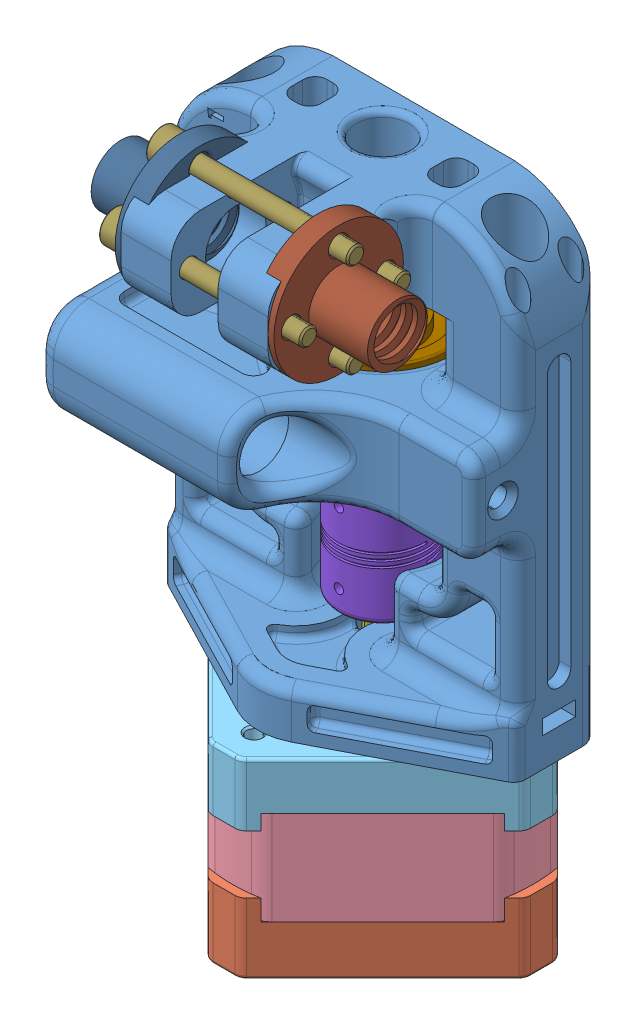
SolidWorks assembly x lead motor block, configuration Default. Lengths in mm.
Overall size (60.87 113.5 61.7).
20 component instances, 12 part files, 15 mates.
Components (placement in the parent):
- x motor lead-1: x motor lead [Default] at (-4.722 9.0941 85.25) size (60.87 77.79 39.41)
- 17HS13-0404S-1: 17HS13-0404S [По умолчанию] at (-4.722 -73.4059 92.25) x (0.707107 0 0.707107) z (-0.707107 0 0.707107) size (42 52.5 42)
  - nema17_bottom_33mm-1: nema17_bottom_33mm [По умолчанию] at origin size (42 12 42)
  - radial ball bearing_68_din-1: radial ball bearing_68_din [DIN 625 - 625 - 8,SI,NC,8_68] at (0 5 0) x (0 -1 0) z (0 0 1) size (5 16 16)
  - nema17_middle_33mm-1: nema17_middle_33mm [По умолчанию] at (0 8.5 0) size (42 16 42)
  - nema17_top_33mm-1: nema17_top_33mm [По умолчанию] at (0 24.5 0) size (42 12.6 42)
  - radial ball bearing_68_din-3: radial ball bearing_68_din [DIN 625 - 625 - 8,SI,NC,8_68] at (0 30.6 0) x (0 1 0) z (0 0 1) size (5 16 16)
  - countersunk flat head cross recess screw_din-1: countersunk flat head cross recess screw_din [ISO 7046-1 - M3 x 25 - Z --- 25N] at (15.5 0.6 15.5) x (0 1 0) z (0.546944 0 -0.837169) size (25 5.5 5.5)
  - countersunk flat head cross recess screw_din-2: countersunk flat head cross recess screw_din [ISO 7046-1 - M3 x 25 - Z --- 25N] at (15.5 0.6 -15.5) x (0 1 0) z (0.546944 0 -0.837169) size (25 5.5 5.5)
  - countersunk flat head cross recess screw_din-3: countersunk flat head cross recess screw_din [ISO 7046-1 - M3 x 25 - Z --- 25N] at (-15.5 0.6 15.5) x (0 1 0) z (0.546944 0 -0.837169) size (25 5.5 5.5)
  - countersunk flat head cross recess screw_din-4: countersunk flat head cross recess screw_din [ISO 7046-1 - M3 x 25 - Z --- 25N] at (-15.5 0.6 -15.5) x (0 1 0) z (0.546944 0 -0.837169) size (25 5.5 5.5)
  - nema17_shaft_33mm-1: nema17_shaft_33mm [По умолчанию] at (0 1.5 0) x (-0.412738 0 0.91085) z (-0.91085 0 -0.412738) size (5 51 5)
- 5-8 small-1: 5-8 small [Default] at (-4.722 -30.9059 92.25) x (1 0 0) z (0 1 0) size (15.39 15.39 20)
- instrument ball bearing_68_iso-1: instrument ball bearing_68_iso [ISO 1224 - 100822 - R,8,SI,NC,8_68] at (-4.722 6.5941 92.25) x (0 1 0) z (0 0 1) size (7 22 22)
- LeadScrew Nut 8mm x 2mmPitch (1)-2: LeadScrew Nut 8mm x 2mmPitch (1) [Default] at (-14.722 29.0941 113.25) x (0 0 -1) z (1 0 0) size (22 22 16.05)
- LeadScrew Nut 8mm x 2mmPitch (2)-2: LeadScrew Nut 8mm x 2mmPitch (2) [Default] at (5.278 29.0941 113.25) x (0 0 1) z (-1 0 0) size (22 22 16.05)
- socket head cap screw_iso-7: socket head cap screw_iso [ISO 4762 M3 x 30 - 18N] at (-21.222 37.0941 113.25) size (33 5.5 5.5)
- socket head cap screw_iso-8: socket head cap screw_iso [ISO 4762 M3 x 30 - 18N] at (-21.222 21.0941 113.25) size (33 5.5 5.5)
- socket head cap screw_iso-9: socket head cap screw_iso [ISO 4762 M3 x 30 - 18N] at (-21.222 29.0941 105.25) size (33 5.5 5.5)
- socket head cap screw_iso-10: socket head cap screw_iso [ISO 4762 M3 x 30 - 18N] at (-21.222 29.0941 121.25) size (33 5.5 5.5)
Mates (geometry in assembly coordinates):
- Coincidente2: coincident aligned: plane of 17HS13-0404S-1/nema17_shaft_33mm-1 through (-4.722 -20.9059 92.25) normal (0 1 0); plane of 5-8 small-1 through (-4.722 -20.9059 92.25) normal (0 1 0)
- Concentrico2: concentric anti-aligned: cylinder of 17HS13-0404S-1/nema17_shaft_33mm-1 through (-4.722 -20.9059 92.25) axis (0 -1 0) radius 2.5; cylinder of 5-8 small-1 through (-4.722 -20.9059 92.25) axis (0 1 0) radius 4
- Concentrico3: concentric aligned: cylinder of x motor lead-1 through (-4.722 49.0941 92.25) axis (0 1 0) radius 4.5; cylinder of instrument ball bearing_68_iso-1 through (-4.722 -14.0434 92.25) axis (0 1 0) radius 4
- Coincidente3: coincident anti-aligned: plane of x motor lead-1 through (-4.722 3.0941 92.25) normal (0 1 0); plane of instrument ball bearing_68_iso-1 through (-13.622 3.0941 92.25) normal (0 -1 0)
- Concentrico4: concentric aligned: cylinder of 5-8 small-1 through (-4.722 -20.9059 92.25) axis (0 1 0) radius 4; cylinder of instrument ball bearing_68_iso-1 through (-4.722 -14.0434 92.25) axis (0 1 0) radius 4
- Concentrico10: concentric anti-aligned: cylinder of LeadScrew Nut 8mm x 2mmPitch (1)-2 through (-18.222 29.0941 113.25) axis (1 0 0) radius 11; cylinder of LeadScrew Nut 8mm x 2mmPitch (2)-2 through (8.778 29.0941 113.25) axis (-1 0 0) radius 11
- Concentrico12: concentric anti-aligned: cylinder of LeadScrew Nut 8mm x 2mmPitch (1)-2 through (-18.222 37.0941 113.25) axis (1 0 0) radius 1.75; cylinder of socket head cap screw_iso-7 through (-52.972 37.0941 113.25) axis (-1 0 0) radius 2.75
- Coincidente13: coincident anti-aligned: plane of LeadScrew Nut 8mm x 2mmPitch (1)-2 through (-18.222 29.0941 113.25) normal (-1 0 0); plane of socket head cap screw_iso-7 through (-18.222 39.8441 113.25) normal (1 0 0)
- Concentrico13: concentric anti-aligned: cylinder of LeadScrew Nut 8mm x 2mmPitch (1)-2 through (-18.222 21.0941 113.25) axis (1 0 0) radius 1.75; cylinder of socket head cap screw_iso-8 through (-52.972 21.0941 113.25) axis (-1 0 0) radius 2.75
- Coincidente14: coincident anti-aligned: plane of LeadScrew Nut 8mm x 2mmPitch (1)-2 through (-18.222 29.0941 113.25) normal (-1 0 0); plane of socket head cap screw_iso-8 through (-18.222 23.8441 113.25) normal (1 0 0)
- Concentrico14: concentric anti-aligned: cylinder of LeadScrew Nut 8mm x 2mmPitch (1)-2 through (-18.222 29.0941 105.25) axis (1 0 0) radius 1.75; cylinder of socket head cap screw_iso-9 through (-52.972 29.0941 105.25) axis (-1 0 0) radius 2.75
- Coincidente15: coincident anti-aligned: plane of LeadScrew Nut 8mm x 2mmPitch (1)-2 through (-18.222 29.0941 113.25) normal (-1 0 0); plane of socket head cap screw_iso-9 through (-18.222 31.8441 105.25) normal (1 0 0)
- Concentrico15: concentric anti-aligned: cylinder of LeadScrew Nut 8mm x 2mmPitch (1)-2 through (-18.222 29.0941 121.25) axis (1 0 0) radius 1.75; cylinder of socket head cap screw_iso-10 through (-52.972 29.0941 121.25) axis (-1 0 0) radius 2.75
- Coincidente16: coincident anti-aligned: plane of LeadScrew Nut 8mm x 2mmPitch (1)-2 through (-18.222 29.0941 113.25) normal (-1 0 0); plane of socket head cap screw_iso-10 through (-18.222 31.8441 121.25) normal (1 0 0)
- Concentrico16: concentric aligned: cylinder of x motor lead-1 through (-26.6423 -35.9059 92.25) axis (0 -1 0) radius 1.6; cylinder of 17HS13-0404S-1/nema17_top_33mm-1 through (-26.6423 -40.9059 92.25) axis (0 -1 0) radius 1.25
